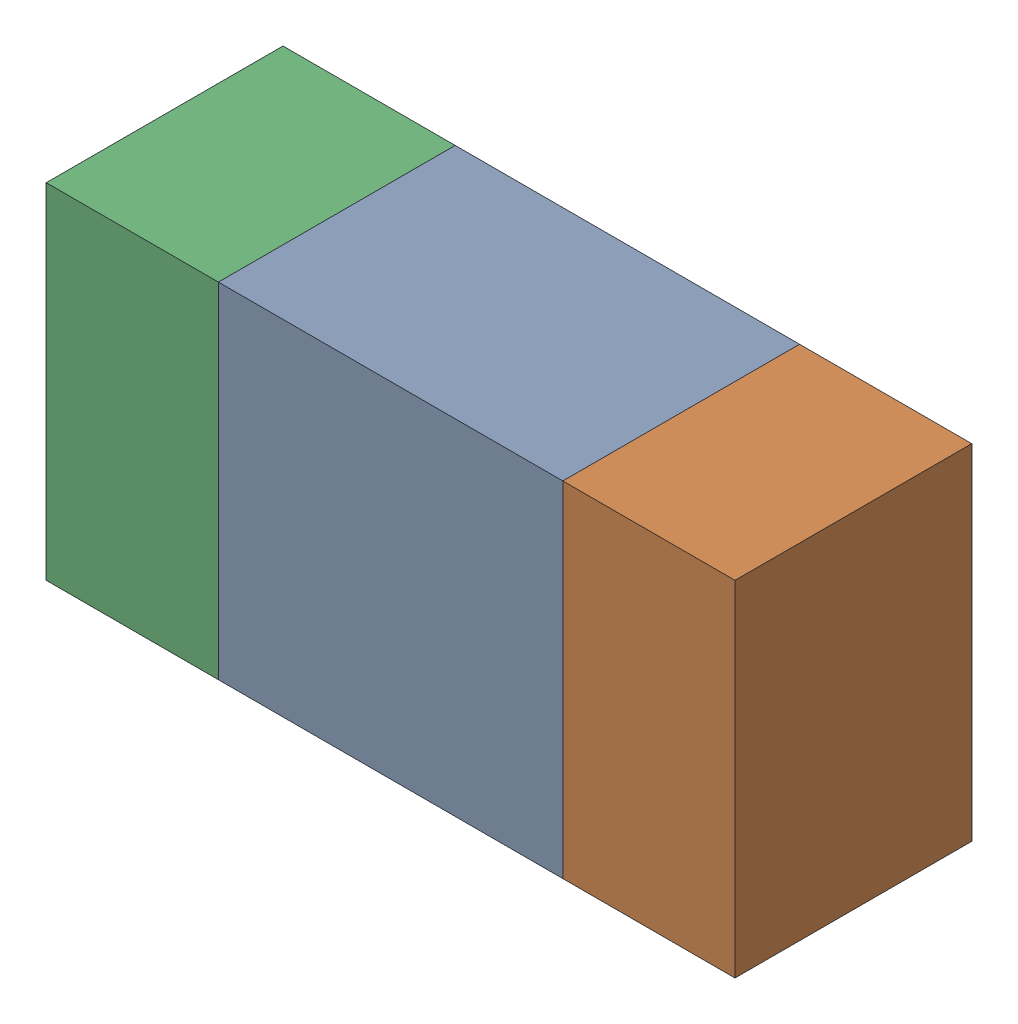
SolidWorks assembly R72, configuration ﾃﾞﾌｫﾙﾄ. Lengths in mm.
Overall size (1.6 0.8 0.55).
6 component instances, 2 part files, 0 mates.
Components (placement in the parent):
- 689261648-1: 689261648 [ﾃﾞﾌｫﾙﾄ] at (68.9 10.9501 0) size (0.8 0.8 0.55)
  - Extruded_33-1: Extruded_33 [ﾃﾞﾌｫﾙﾄ] at origin size (0.8 0.8 0.55)
- 689261512-1: 689261512 [ﾃﾞﾌｫﾙﾄ] at (69.5001 10.9501 0) size (0.4 0.8 0.55)
  - Extruded_32-1: Extruded_32 [ﾃﾞﾌｫﾙﾄ] at origin size (0.4 0.8 0.55)
- 689261512-2: 689261512 [ﾃﾞﾌｫﾙﾄ] at (68.3001 10.9501 0) size (0.4 0.8 0.55)
  - Extruded_32-1: Extruded_32 [ﾃﾞﾌｫﾙﾄ] at origin size (0.4 0.8 0.55)
